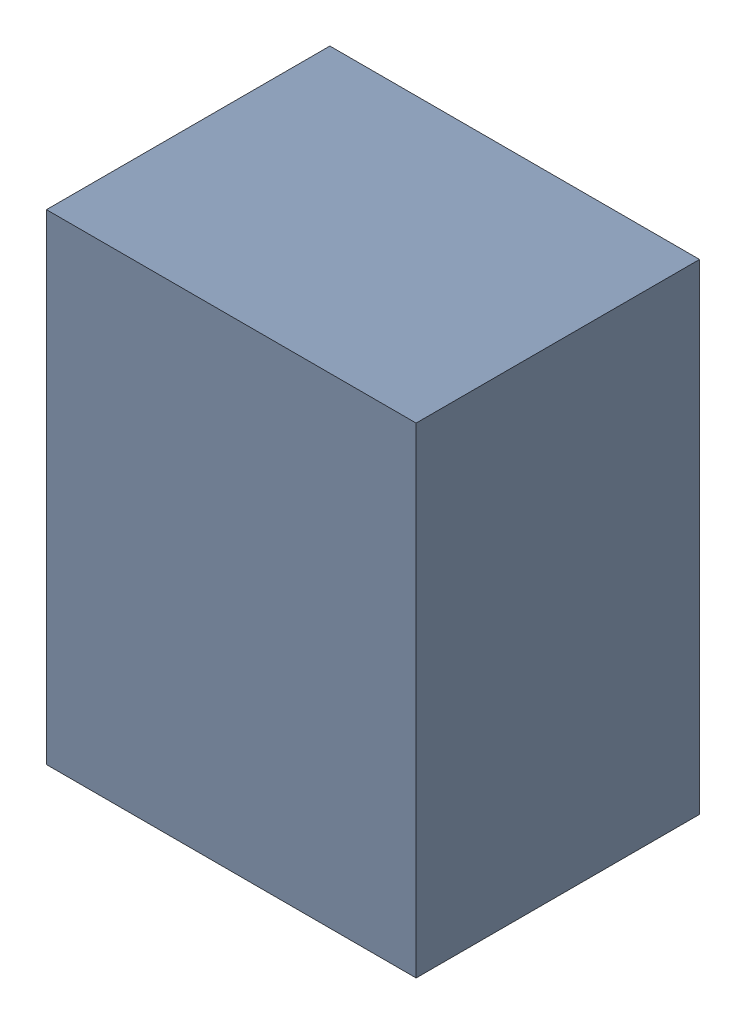
SolidWorks assembly D9, configuration Default. Lengths in mm.
Overall size (1.5 1.95 1.15).
2 component instances, 1 part files, 0 mates.
Components (placement in the parent):
- 870943840-1: 870943840 [Default] at (80.0092 19.4796 0) size (1.5 1.95 1.15)
  - Extruded_31-1: Extruded_31 [Default] at origin size (1.5 1.95 1.15)
